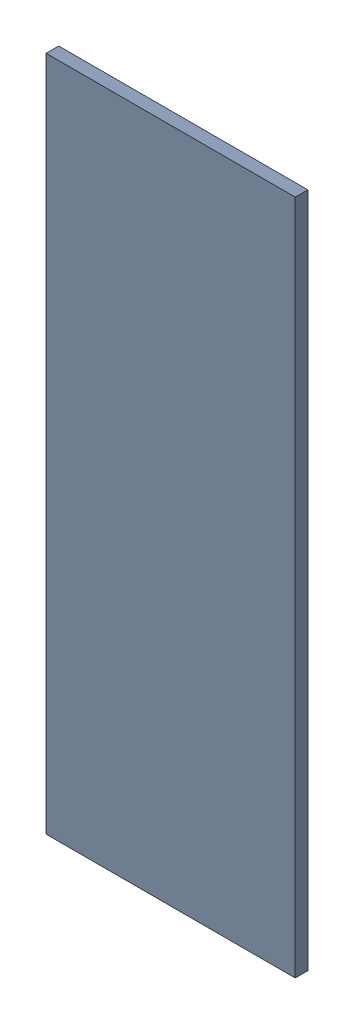
SolidWorks assembly Pad RAK4600-20(24.975mm,8.691mm) on Top Layer, configuration Predeterminado. Lengths in mm.
Overall size (0.7 1.9 0.04).
2 component instances, 1 part files, 0 mates.
Components (placement in the parent):
- Pad RAK4600-20(24.975mm,8.691mm) on Top Layer-1-1: Pad RAK4600-20(24.975mm,8.691mm) on Top Layer-1 [Predeterminado] at (-68.317 -44.187 -0.0457) size (0.7 1.9 0.04)
  - Pad RAK4600-20(24.975mm,8.691mm) on Top Layer-Part-1-1: Pad RAK4600-20(24.975mm,8.691mm) on Top Layer-Part-1 [Predeterminado] at origin size (0.7 1.9 0.04)
